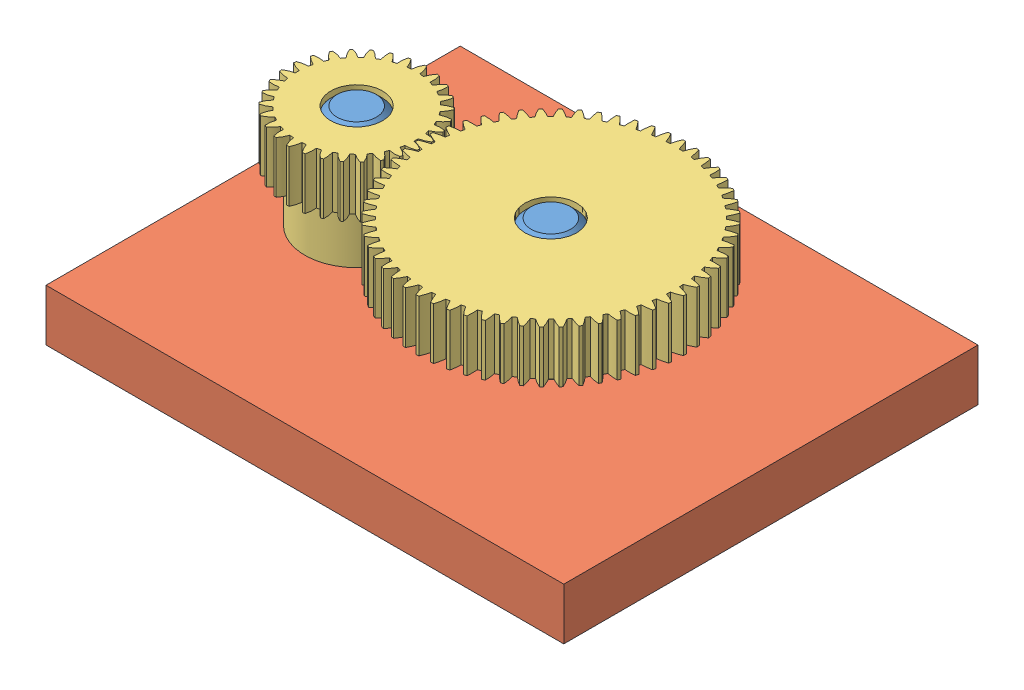
SolidWorks assembly Schoolwork - Module 2, configuration Default. Lengths in mm.
Overall size (127 38.1 101.6).
5 component instances, 3 part files, 9 mates.
Components (placement in the parent):
- Gear - Shaft-1: Gear - Shaft [Default] at (10.783 16.4546 34.2957) size (12.7 38.1 12.7)
- Gear-Support Plate-1: Gear-Support Plate [Default] at (48.883 -2.5954 34.2957) size (127 12.7 101.6)
- Gear - Shaft-2: Gear - Shaft [Default] at (58.408 16.4546 34.2957) size (12.7 38.1 12.7)
- spur gear_ai-1: spur gear_ai [Inch - Spur gear 24DP 30T 20PA 0.5FW ---S30O1H1L0.5N] at (10.783 22.8046 34.2957) x (0 1 0) z (-0.590323 0 -0.807167) size (25.4 33.74 33.87)
- spur gear_ai-2: spur gear_ai [Inch - Spur gear 24DP 60T 20PA 0.5FW ---S60O1H1L0.5N] at (58.408 22.8046 34.2957) x (0 1 0) z (0.256654 0 -0.966503) size (25.4 65.56 65.56)
Mates (geometry in assembly coordinates):
- Concentric1: concentric anti-aligned: cylinder of Gear - Shaft-1 through (10.783 35.5046 34.2957) axis (0 -1 0) radius 6.35; cylinder of Gear-Support Plate-1 through (10.783 -2.5954 34.2957) axis (0 1 0) radius 6.35
- Concentric2: concentric anti-aligned: cylinder of Gear-Support Plate-1 through (58.408 -2.5954 34.2957) axis (0 1 0) radius 6.35; cylinder of Gear - Shaft-2 through (58.408 35.5046 34.2957) axis (0 -1 0) radius 6.35
- Coincident1: coincident aligned: plane of Gear - Shaft-1 through (10.783 -2.5954 34.2957) normal (0 -1 0); plane of Gear-Support Plate-1 through (48.883 -2.5954 34.2957) normal (0 -1 0)
- Coincident2: coincident aligned: plane of Gear-Support Plate-1 through (48.883 -2.5954 34.2957) normal (0 -1 0); plane of Gear - Shaft-2 through (58.408 -2.5954 34.2957) normal (0 -1 0)
- Coincident3: coincident anti-aligned: plane of Gear-Support Plate-1 through (48.883 10.1046 34.2957) normal (0 1 0); plane of spur gear_ai-2 through (58.408 10.1046 34.2957) normal (0 -1 0)
- Coincident4: coincident anti-aligned: plane of Gear-Support Plate-1 through (48.883 10.1046 34.2957) normal (0 1 0); plane of spur gear_ai-1 through (10.783 10.1046 34.2957) normal (0 -1 0)
- Concentric6: concentric aligned: cylinder of Gear - Shaft-2 through (58.408 35.5046 34.2957) axis (0 -1 0) radius 6.35; cylinder of spur gear_ai-2 through (58.408 48.2047 34.2957) axis (0 -1 0) radius 6.35
- Concentric7: concentric aligned: cylinder of Gear - Shaft-1 through (10.783 35.5046 34.2957) axis (0 -1 0) radius 6.35; cylinder of spur gear_ai-1 through (10.783 48.2047 34.2957) axis (0 -1 0) radius 6.35
- GearMate1: gear = 2 : 1 mm: cylinder of spur gear_ai-1 through (10.783 48.2047 34.2957) axis (0 -1 0) radius 6.35; cylinder of spur gear_ai-2 through (58.408 48.2047 34.2957) axis (0 -1 0) radius 6.35
